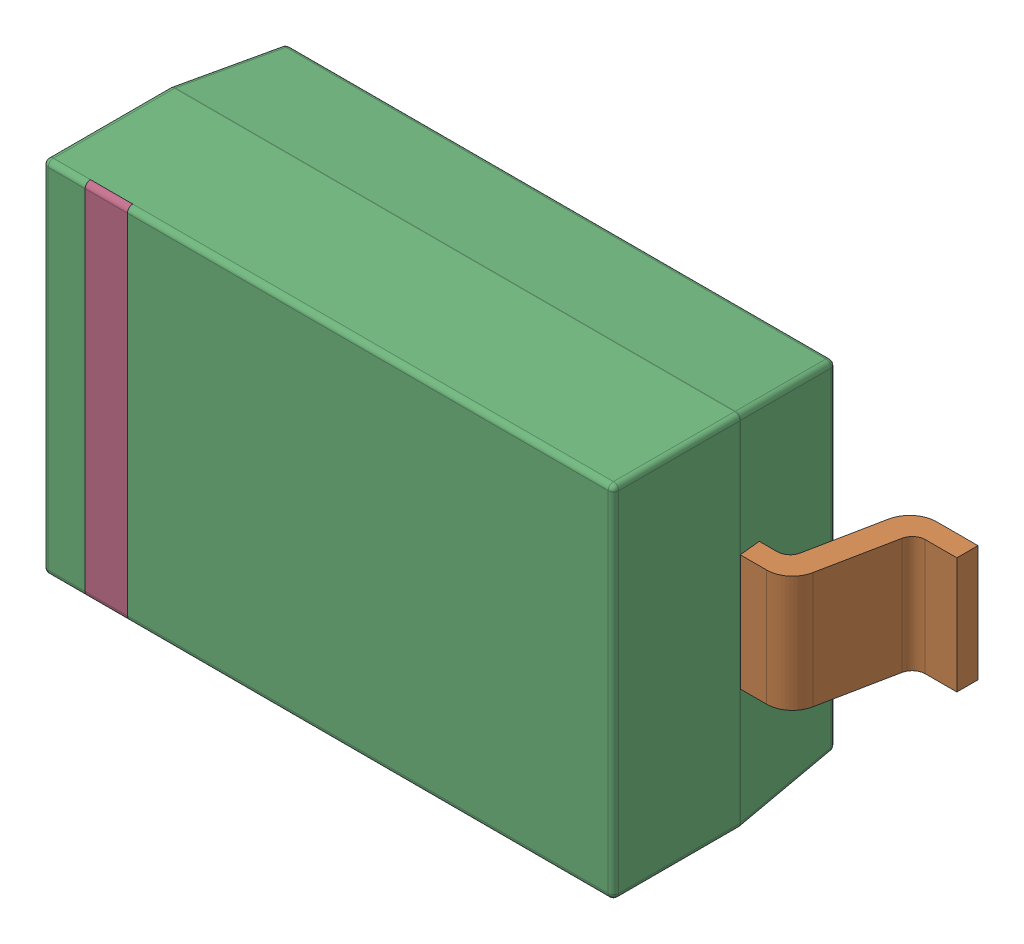
SolidWorks assembly D5, configuration Default. Lengths in mm.
Overall size (3.75 1.71 1.2).
5 component instances, 4 part files, 0 mates.
Components (placement in the parent):
- sod123_v4-1: sod123_v4 [Default] at (27.9841 20.0661 0) x (1 0 0) z (0 0 1) size (3.75 1.71 1.2)
  - pin-1: pin [Default] at (-0.675 -0.875 0) x (0 -1 0) z (0 0 1) size (0.55 0.55 0.6)
  - pin(Mirror)-1: pin(Mirror) [Default] at (0.675 -0.875 0) x (0 -1 0) z (0 0 -1) size (0.55 0.55 0.6)
  - icbody-1: icbody [Default] at origin size (2.71 1.71 1.11)
  - Component5-1: Component5 [Default] at origin size (0.2 1.7 0.02)
